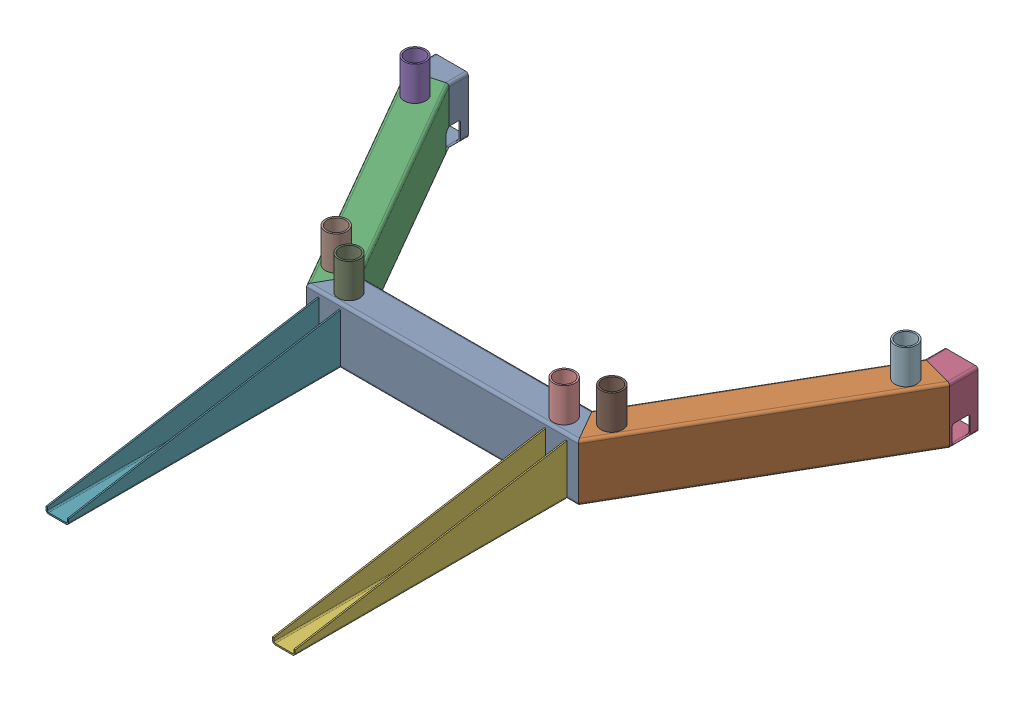
SolidWorks assembly GE-16005_ASM, configuration Default. Lengths in mm.
Overall size (1219.2 203.2 1201.03).
13 component instances, 7 part files, 0 mates.
Components (placement in the parent):
- GE-16005-01-1: GE-16005-01 [Default] at origin size (609.6 127 76.2)
- GE-16005-02-1: GE-16005-02 [Default] at (304.8 63.5 38.1) x (0.5 0 -0.866025) z (0.866025 0 0.5) size (609.6 127 76.2)
- GE-16005-03-1: GE-16005-03 [Default] at (-304.8 -63.5 38.1) x (-0.5 0 -0.866025) z (-0.866025 0 0.5) size (609.6 127 76.2)
- GE-16005-04-1: GE-16005-04 [Default] at (609.6 63.5 -489.8291) x (0 0 -1) z (1 0 0) size (63.5 127 76.2)
- GE-16005-05-1: GE-16005-05 [Default] at (-550.3537 -63.5 -450.7115) size (48.26 203.2 48.26)
- GE-16005-06-1: GE-16005-06 [Default] at (254 -63.5 647.7) size (50.8 114.3 609.6)
- GE-16005-06-2: GE-16005-06 [Default] at (-254 -63.5 647.7) size (50.8 114.3 609.6)
- GE-16005-05-2: GE-16005-05 [Default] at (-309.0537 -63.5 -32.7676) size (48.26 203.2 48.26)
- GE-16005-05-3: GE-16005-05 [Default] at (-241.3 -63.5 6.35) size (48.26 203.2 48.26)
- GE-16005-05-4: GE-16005-05 [Default] at (241.3 -63.5 6.35) size (48.26 203.2 48.26)
- GE-16005-05-5: GE-16005-05 [Default] at (309.0537 -63.5 -32.7676) size (48.26 203.2 48.26)
- GE-16005-05-6: GE-16005-05 [Default] at (550.3537 -63.5 -450.7115) size (48.26 203.2 48.26)
- GE-16005-07-1: GE-16005-07 [Default] at (-609.6 -63.5 -489.8291) x (0 0 -1) z (-1 0 0) size (63.5 127 76.2)
